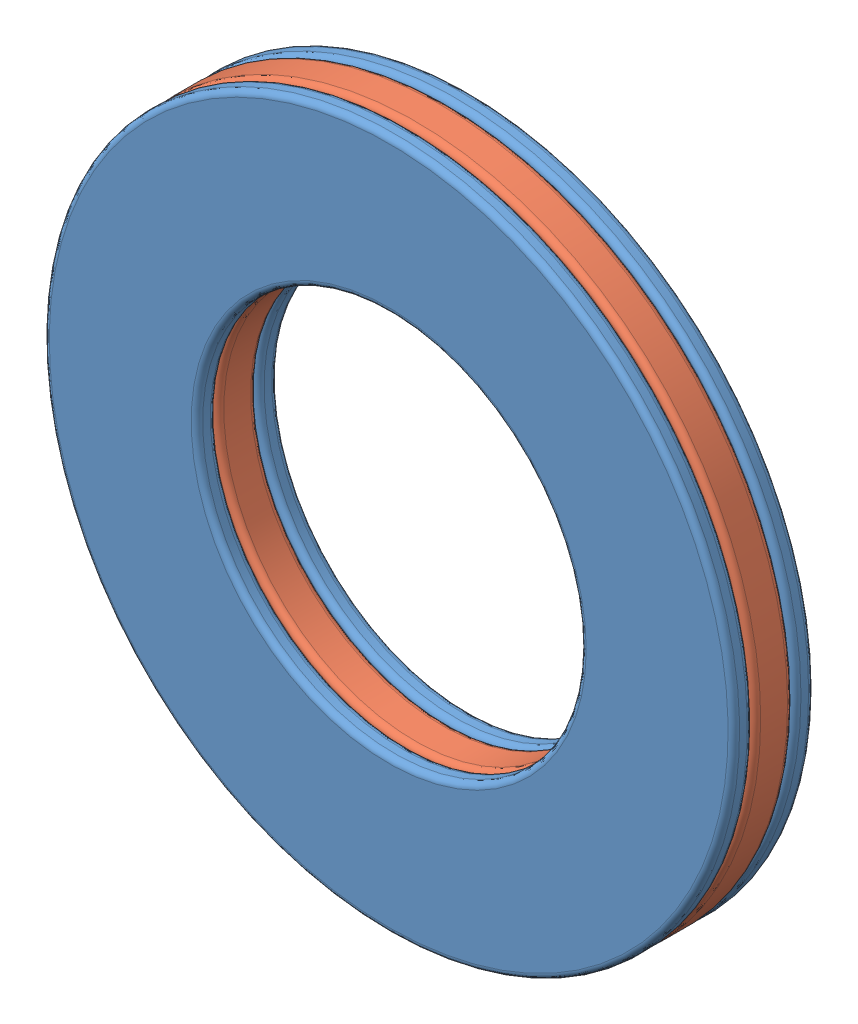
SolidWorks assembly Опорный_подшипник, configuration Default. Lengths in mm.
Overall size (39.69 39.69 4.2).
3 component instances, 2 part files, 5 mates.
Components (placement in the parent):
- Деталь1^Опорный_подшипник-1: Деталь1^Опорный_подшипник [По умолчанию] at origin size (36 36 1) (virtual)
- Деталь2^Опорный_подшипник-1: Деталь2^Опорный_подшипник [По умолчанию] at (0 0 1.1) size (36 36 2) (virtual)
- Деталь1^Опорный_подшипник-2: Деталь1^Опорный_подшипник [По умолчанию] at (0 0 3.2) x (0.994117 0.108314 0) z (0 0 1) size (36 36 1) (virtual)
Mates (geometry in assembly coordinates):
- Совпадение7: coordinate: point of Деталь1^Сборка1-1
- Расстояние1: distance = 0.1 mm anti-aligned: plane of Деталь2^Сборка1-1 through (0 0 1.1) normal (0 0 -1); plane of Деталь1^Сборка1-1 through (0 0 1) normal (0 0 1)
- Концентричный1: concentric aligned: cylinder of Деталь1^Сборка1-1 through (0 0 1) axis (0 0 -1) radius 10; cylinder of Деталь2^Сборка1-1 through (0 0 3.1) axis (0 0 -1) radius 10
- Расстояние2: distance = 0.1 mm anti-aligned: plane of Деталь1^Сборка1-2 through (0 0 3.2) normal (0 0 -1); plane of Деталь2^Сборка1-1 through (0 0 3.1) normal (0 0 1)
- Концентричный2: concentric aligned: cylinder of Деталь2^Сборка1-1 through (0 0 3.1) axis (0 0 -1) radius 10; cylinder of Деталь1^Сборка1-2 through (0 0 4.2) axis (0 0 -1) radius 10
